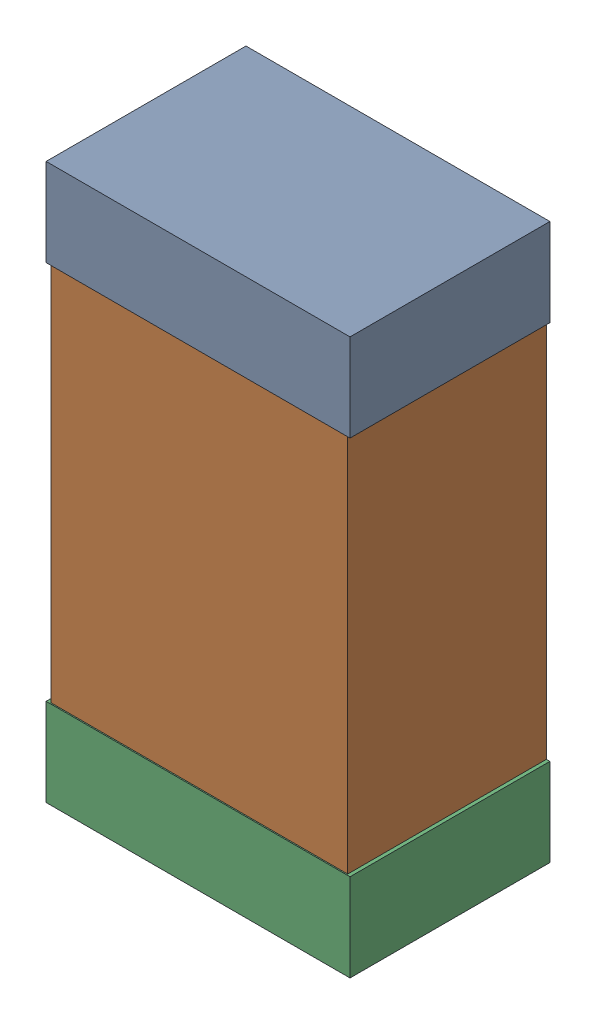
SolidWorks assembly R3_Motor_7Kanaloa_v2.0.0_Loko, configuration Default. Lengths in mm.
Overall size (1.3 2.38 0.85).
6 component instances, 2 part files, 0 mates.
Components (placement in the parent):
- 330415056_1-1: 330415056_1 [Default] at (97.0907 80.2144 0) size (1.3 0.38 0.85)
  - Extruded_29-1: Extruded_29 [Default] at origin size (1.3 0.38 0.85)
- 334787376_1-1: 334787376_1 [Default] at (97.0907 79.2144 0) size (1.27 2.2 0.85)
  - Extruded_30-1: Extruded_30 [Default] at origin size (1.27 2.2 0.85)
- 330415056_1-2: 330415056_1 [Default] at (97.0907 78.2144 0) size (1.3 0.38 0.85)
  - Extruded_29-1: Extruded_29 [Default] at origin size (1.3 0.38 0.85)
